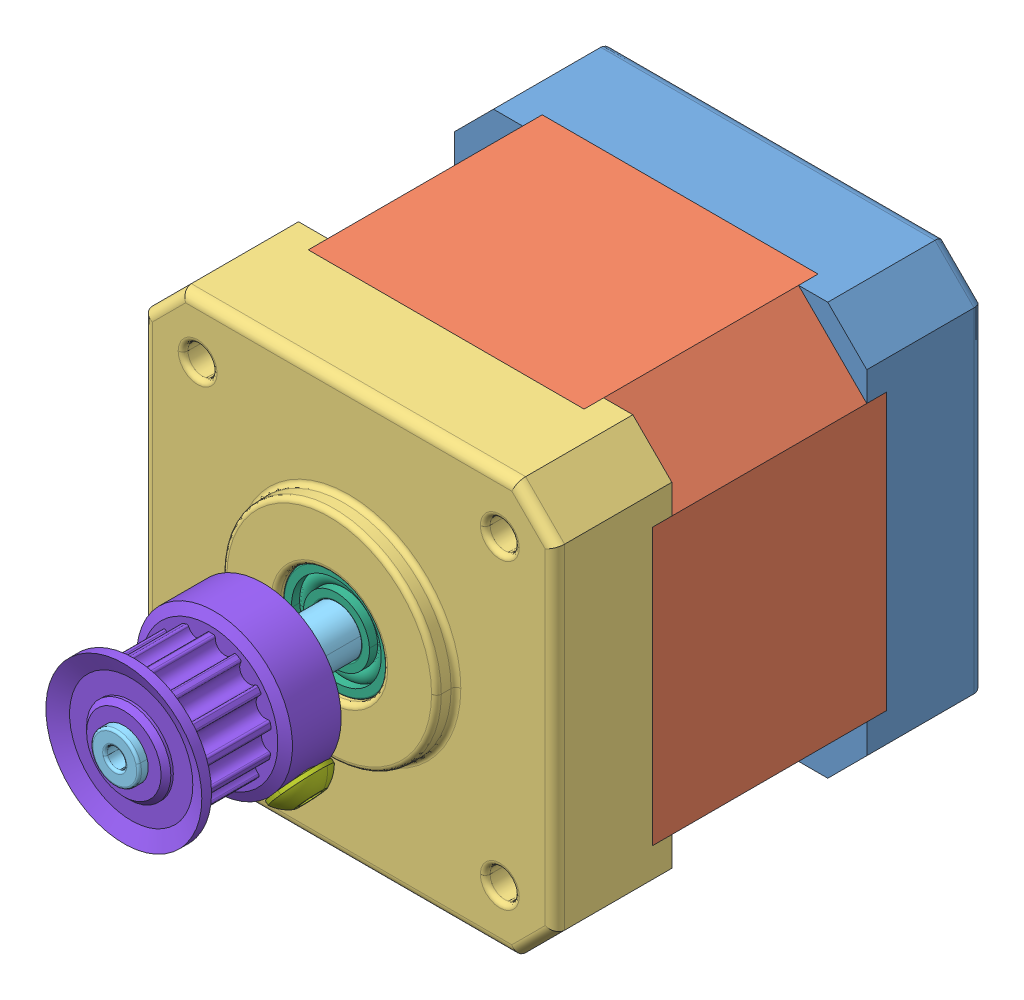
SolidWorks assembly NEMA 17 with T5 Pulley, configuration Predeterminado. Lengths in mm.
Overall size (42.3 42.3 68).
13 component instances, 8 part files, 0 mates.
Components (placement in the parent):
- NEMA 17 with T5 Pulley.STEP-1: NEMA 17 with T5 Pulley.STEP [Predeterminado] at origin size (42.3 42.3 68)
  - Base.STEP-1: Base.STEP [Predeterminado] at (-10.3955 4.6172 0) size (42.3 42.3 12)
  - Cuerpo.STEP-1: Cuerpo.STEP [Predeterminado] at (-10.3955 4.6172 10) size (42.3 42.3 24)
  - Tapa.STEP-1: Tapa.STEP [Predeterminado] at (-10.3955 4.6172 44) x (-1 0 0) z (0 0 -1) size (42.3 42.3 14)
  - pan cross head_am_B18.6.7M - M3 x 0.5 x 5 Type I Cross Recessed PHMS --5N.STEP-1: pan cross head_am_B18.6.7M - M3 x 0.5 x 5 Type I Cross Recessed PHMS --5N.STEP [Predeterminado] at (5.1045 20.1172 0.6) x (0 0 1) z (-0.896 0.444054 0) size (7.37 5.6 5.6)
  - pan cross head_am_B18.6.7M - M3 x 0.5 x 5 Type I Cross Recessed PHMS --5N.STEP-2: pan cross head_am_B18.6.7M - M3 x 0.5 x 5 Type I Cross Recessed PHMS --5N.STEP [Predeterminado] at (-25.8955 20.1172 0.6) x (0 0 1) z (-0.859432 0.51125 0) size (7.37 5.6 5.6)
  - pan cross head_am_B18.6.7M - M3 x 0.5 x 5 Type I Cross Recessed PHMS --5N.STEP-3: pan cross head_am_B18.6.7M - M3 x 0.5 x 5 Type I Cross Recessed PHMS --5N.STEP [Predeterminado] at (-25.8955 -10.8828 0.6) x (0 0 1) z (-0.91385 -0.406051 0) size (7.37 5.6 5.6)
  - pan cross head_am_B18.6.7M - M3 x 0.5 x 5 Type I Cross Recessed PHMS --5N.STEP-4: pan cross head_am_B18.6.7M - M3 x 0.5 x 5 Type I Cross Recessed PHMS --5N.STEP [Predeterminado] at (5.1045 -10.8828 0.6) x (0 0 1) z (-0.883632 0.468182 0) size (7.37 5.6 5.6)
  - Eje.STEP-1: Eje.STEP [Predeterminado] at (-10.3955 4.6172 0) x (0.958977 0.283482 0) z (0 0 1) size (5 5 68)
  - instrument ball bearing_68_am_AFBMA 12.1.4.1 - 0050-11 - 10,SI,NC,10_68.STEP-1: instrument ball bearing_68_am_AFBMA 12.1.4.1 - 0050-11 - 10,SI,NC,10_68.STEP [Predeterminado] at (-10.3955 4.6172 43.7649) x (0 0 -1) z (0.998898 0.04694 0) size (3 11 11)
  - instrument ball bearing_68_am_AFBMA 12.1.4.1 - 0050-11 - 10,SI,NC,10_68.STEP-2: instrument ball bearing_68_am_AFBMA 12.1.4.1 - 0050-11 - 10,SI,NC,10_68.STEP [Predeterminado] at (-10.3955 4.6172 2.401) x (0 0 1) z (-0.993665 0.112385 0) size (3 11 11)
  - socket button head cap screw_am_B18.3.4M - 3 x 0.5 x 5 SBHCS --N.STEP-1: socket button head cap screw_am_B18.3.4M - 3 x 0.5 x 5 SBHCS --N.STEP [Predeterminado] at (-3.0242 -1.6107 55.2724) x (-0.763867 0.645374 0) z (0.206777 0.244742 0.947283) size (6.65 5.7 5.7)
  - T5 Pulley.STEP-1: T5 Pulley.STEP [Predeterminado] at (-10.3955 4.6172 52.2724) x (0 0 1) z (0.763867 -0.645374 0) size (14.8 16 16.01)
